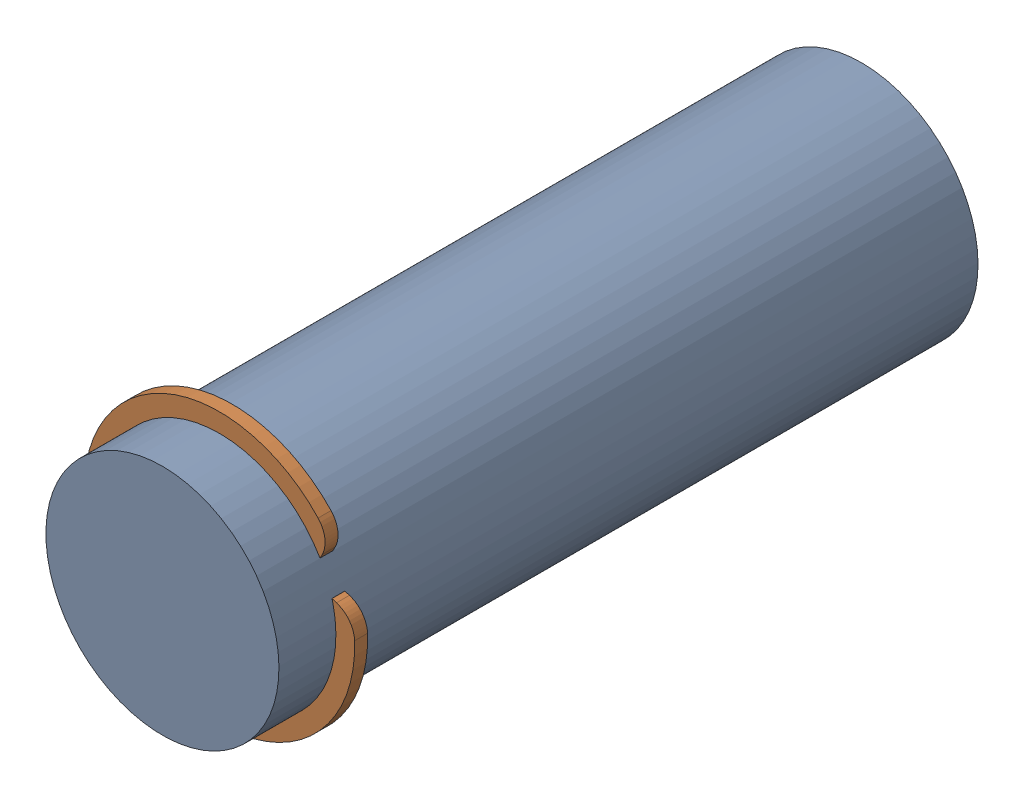
SolidWorks assembly small rod with snap rings, configuration Default. Lengths in mm.
Overall size (7.45 7.53 15).
2 component instances, 2 part files, 1 mates.
Components (placement in the parent):
- PLA rod at joint 15mm-1: PLA rod at joint 15mm [Default] at (-72.1489 119.7367 6.2367) x (0.807473 0.589904 0) z (0 0 1) size (5 5 15)
- snap ring used 5mm -1: snap ring used 5mm  [Default] at (-62.9673 123.5442 -6.1244) x (0 0 1) z (-0.923728 -0.38305 0) size (0.28 5.81 5.65)
Mates (geometry in assembly coordinates):
- Concentric1290: concentric aligned: cylinder of PLA rod at joint 15mm-1 through (-72.1489 119.7367 13.7367) axis (0 0 -1) radius 2.5; cylinder of snap ring used 5mm -2 through (-72.1489 119.7367 0.2367) axis (0 0 -1) radius 2.5
